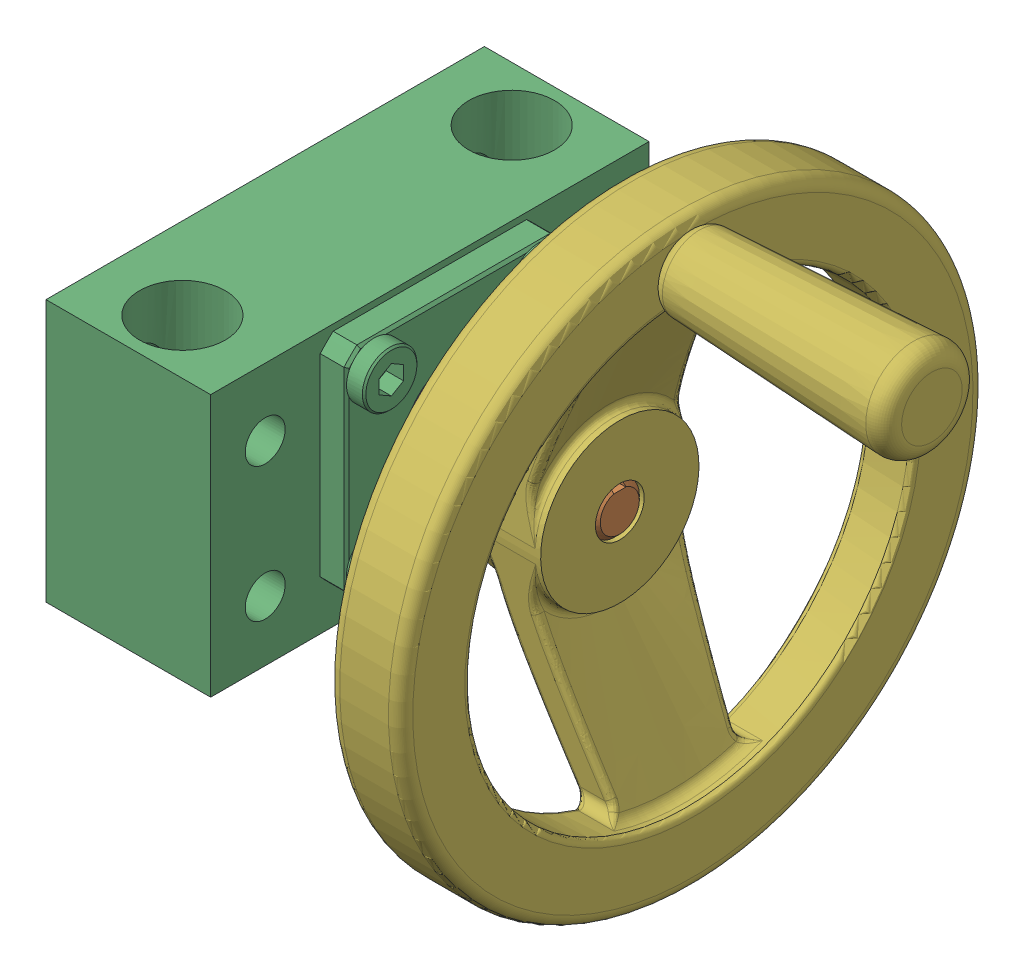
SolidWorks assembly EndCode2_17-EQ, configuration Valor predeterminado. Lengths in mm.
Overall size (176.02 159.33 156.87).
6 component instances, 6 part files, 0 mates.
Components (placement in the parent):
- Place Holder-1: Place Holder [Valor predeterminado] at origin size (0.38 0.51 0.51)
- EndMachining_17-3K-1: EndMachining_17-3K [Valor predeterminado] x (0 0 1) z (-1 0 0) size (17.01 17.01 92.71)
- EZM_EZM-3017-1: EZM_EZM-3017 [Valor predeterminado] at (43.18 -38.1 57.15) x (0 0 -1) z (1 0 0) size (114.3 68.33 54.36)
- LockNut(1)_N-03-1: LockNut(1)_N-03 [Valor predeterminado] at (48.514 0 0) x (1 0 0) z (0 0.998865 0.047634) size (8.64 28.41 28.51)
- H06x-1: H06x [Valor predeterminado] at (60.96 0 0) x (1 0 0) z (0 -0.029232 0.999573) size (115.06 154.95 152.4)
- Spacer2-1: Spacer2 [Valor predeterminado] at origin size (48.51 22.35 22.35)
